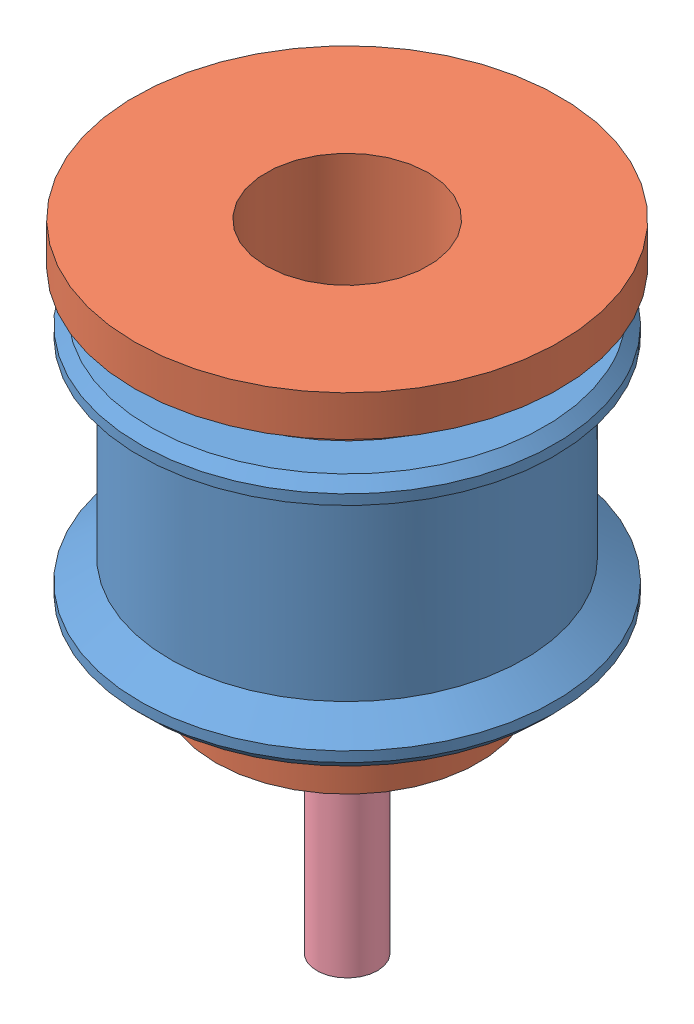
SolidWorks assembly belt tensioner assembly, configuration Default. Lengths in mm.
Overall size (27.67 31.4 27.67).
4 component instances, 4 part files, 7 mates.
Components (placement in the parent):
- belt tensioner pulley-1: belt tensioner pulley [Default] at (0 9.75 0) x (-0.886174 0 0.463352) z (0 -1 0) size (20.5 20.5 12.5)
- belt tensioner base-1: belt tensioner base [Default] at origin size (21 20 21)
- M3 METAL washer-1: M3 METAL washer [Default] at (0 4 0) size (7 0.6 7)
- M3x16 METAL bolt-1: M3x16 METAL bolt [Default] at (0 -11.4 0) x (-0.239711 0 0.970844) z (-0.970844 0 -0.239711) size (5.4 19 5.4)
Mates (geometry in assembly coordinates):
- Concentric10: concentric anti-aligned: cylinder of belt tensioner pulley-1 through (0 4.5 0) axis (0 1 0) radius 6.75; cylinder of belt tensioner base-1 through (0 20 0) axis (0 -1 0) radius 6.5
- Distance1: distance = 2 mm anti-aligned: plane of belt tensioner pulley-1 through (0 16 0) normal (0 1 0); plane of belt tensioner base-1 through (0 18 0) normal (0 -1 0)
- Coincident10: coincident anti-aligned: plane of belt tensioner base-1 through (0 4 0) normal (0 1 0); plane of M3 METAL washer-1 through (0 4 0) normal (0 -1 0)
- Concentric12: concentric anti-aligned: cylinder of belt tensioner base-1 through (0 -11.3137 0) axis (0 1 0) radius 4; cylinder of M3 METAL washer-1 through (0 4.6 0) axis (0 -1 0) radius 1.65
- Concentric14: concentric anti-aligned: cylinder of belt tensioner base-1 through (0 -11.3137 0) axis (0 1 0) radius 4; cylinder of M3x16 METAL bolt-1 through (0 4.6 0) axis (0 -1 0) radius 1.5
- Coincident12: coincident anti-aligned: plane of M3 METAL washer-1 through (0 4.6 0) normal (0 1 0); plane of M3x16 METAL bolt-1 through (0 4.6 0) normal (0 -1 0)
- Coincident13: coordinate: point of stepper belt idler base v5-1
